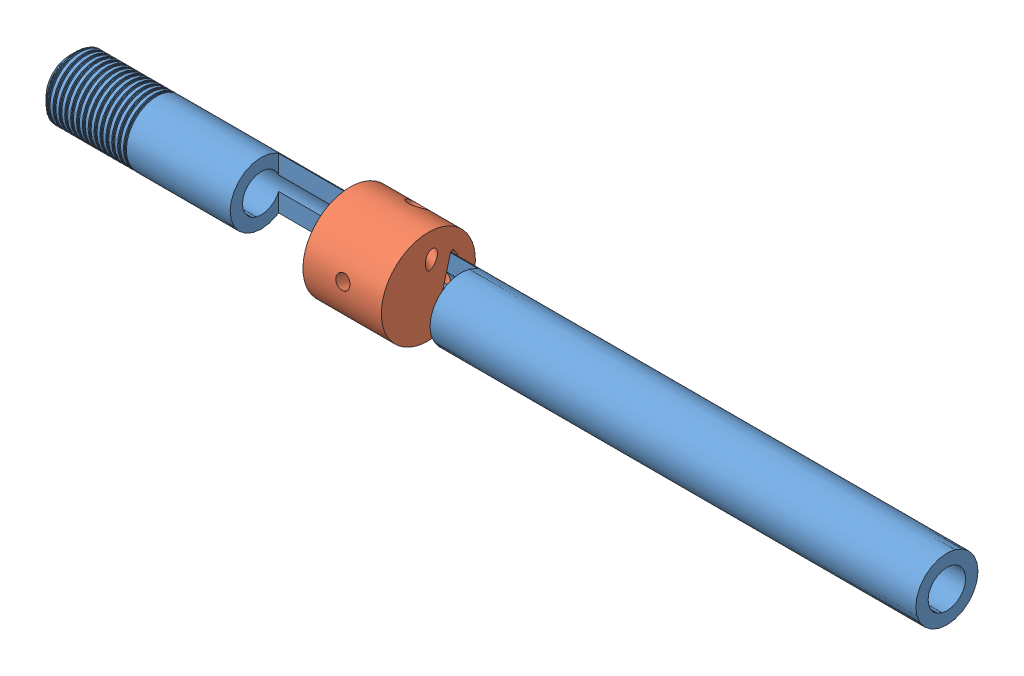
SolidWorks assembly slider assembly v-2 30-Oct-2017, configuration Default. Lengths in mm.
Overall size (136.43 15.15 14.94).
2 component instances, 2 part files, 2 mates.
Components (placement in the parent):
- wheel_handle_body_slider v-3 01-Nov-2017-1: wheel_handle_body_slider v-3 01-Nov-2017 [Default] at (0.302 73.1422 98.3877) size (112 8.19 8.13)
- slider v-4 02-Nov-2017-1: slider v-4 02-Nov-2017 [Default] at (24.7367 68.6039 58.5619) x (1 0 0) z (0 0.26153 0.965195) size (112 12.42 12.11)
Mates (geometry in assembly coordinates):
- Coincident3: coincident anti-aligned: line of wheel_handle_body_slider v-3 01-Nov-2017-1 through (12.802 76.4328 96.1689) axis (1 0 0); line of slider v-4 02-Nov-2017-1 through (34.7367 76.4328 96.1689) axis (-1 0 0)
- Parallel1: parallel: plane of wheel_handle_body_slider v-3 01-Nov-2017-1 through (12.802 69.1734 96.1689) normal (0 0 1); plane of slider v-4 02-Nov-2017-1 through (36.0721 76.4328 100.1689) normal (0 0 1)
